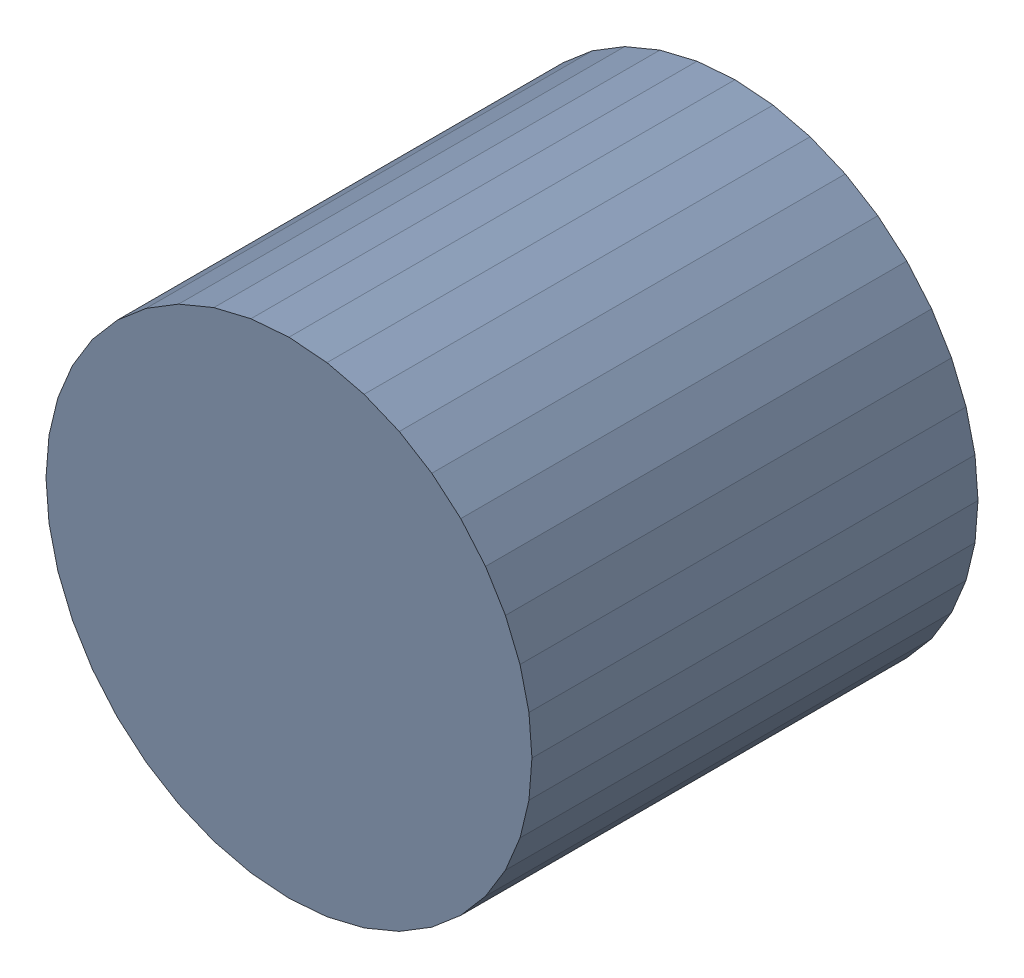
SolidWorks assembly USB23_C5, configuration Default. Lengths in mm.
Overall size (6.32 6.32 5.8).
2 component instances, 1 part files, 0 mates.
Components (placement in the parent):
- 384312384-1: 384312384 [Default] at (149.86 51.943 -6.9024) size (6.32 6.32 5.8)
  - Extruded_7-1: Extruded_7 [Default] at origin size (6.32 6.32 5.8)
